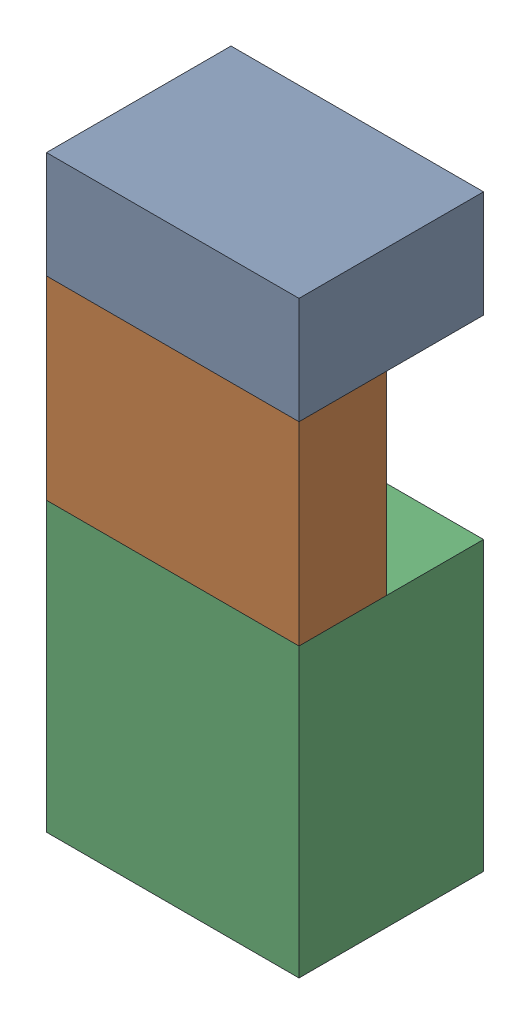
SolidWorks assembly SUP_K16, configuration Default. Lengths in mm.
Overall size (13 30.3 9.5).
6 component instances, 3 part files, 0 mates.
Components (placement in the parent):
- 1151724928-1: 1151724928 [Default] at (245.745 41.975 0) size (13 5.5 9.5)
  - Extruded_2-1: Extruded_2 [Default] at origin size (13 5.5 9.5)
- 1151725064-1: 1151725064 [Default] at (245.745 34.225 5) size (13 10 4.5)
  - Extruded_3-1: Extruded_3 [Default] at origin size (13 10 4.5)
- 1151724792-1: 1151724792 [Default] at (245.745 21.825 0) size (13 14.8 9.5)
  - Extruded_4-1: Extruded_4 [Default] at origin size (13 14.8 9.5)
